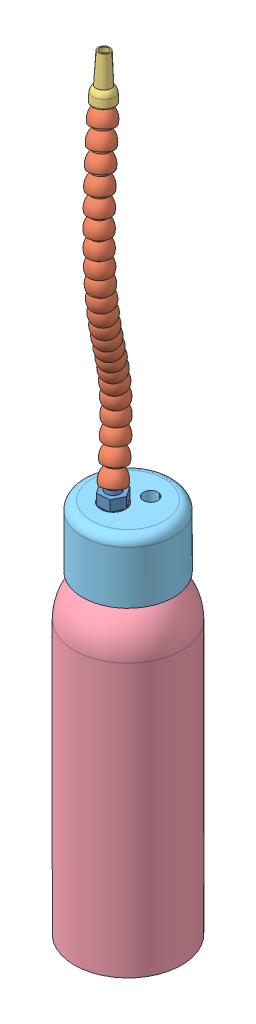
SolidWorks assembly _Robocup_Assembly_Thermos_Static_Wide_Straw_, configuration Default. Lengths in mm.
Overall size (75.21 554.8 95.58).
27 component instances, 5 part files, 7 mates.
Components (placement in the parent):
- Coolant Pipe.stp-1: Coolant Pipe.stp [Default] at (-3.81 14.5 6.5991) x (0.568385 0 0.822762) z (-0.822762 0 0.568385) size (74.23 300.91 26.18)
  - Coolant Bolt.stp-1: Coolant Bolt.stp [Default] x (-1 0 0) z (0 0 1) size (17.61 27.5 15.25)
  - Connectors.stp-1: Connectors.stp [Default] at (-2.2835 3.6671 -0.0362) x (-0.321951 -0.100327 -0.941426) z (0.285439 -0.958386 0.00452) size (18.3 18.3 20)
  - Connectors.stp-2: Connectors.stp [Default] at (-0.9485 62.1668 -0.2193) x (0.834188 -0.338799 0.435138) z (-0.378337 -0.925657 0.00458) size (18.3 18.3 20)
  - Connectors.stp-3: Connectors.stp [Default] at (-7.0218 39.1054 -0.1142) x (0.974617 -0.052931 0.217534) z (-0.054998 -0.99848 0.003454) size (18.3 18.3 20)
  - Connectors.stp-4: Connectors.stp [Default] at (-7.018 27.1423 -0.0887) x (-0.288884 -0.031731 -0.956838) z (0.11095 -0.993826 -0.00054) size (18.3 18.3 20)
  - Connectors.stp-5: Connectors.stp [Default] at (10.0914 83.4503 -0.3173) x (0.525964 -0.304704 -0.794051) z (-0.497138 -0.867664 0.003658) size (18.3 18.3 20)
  - Connectors.stp-6: Connectors.stp [Default] at (4.2645 72.9625 -0.2712) x (0.886562 -0.462353 0.015441) z (-0.462461 -0.88663 0.004202) size (18.3 18.3 20)
  - Connectors.stp-7: Connectors.stp [Default] at (-4.9174 50.8742 -0.1644) x (0.803108 -0.192004 0.56405) z (-0.235547 -0.971852 0.004557) size (18.3 18.3 20)
  - Connectors.stp-8: Connectors.stp [Default] at (16.0513 93.8656 -0.3564) x (0.86534 -0.495122 -0.077724) z (-0.496415 -0.86808 0.003062) size (18.3 18.3 20)
  - Connectors.stp-9: Connectors.stp [Default] at (35.5838 137.5772 -0.4345) x (0.770438 -0.236558 0.592002) z (-0.293738 -0.955886 0.000312) size (18.3 18.3 20)
  - Connectors.stp-10: Connectors.stp [Default] at (38.4122 149.228 -0.4322) x (0.672162 -0.141658 -0.726727) z (-0.20668 -0.978409 -0.000445) size (18.3 18.3 20)
  - Connectors.stp-11: Connectors.stp [Default] at (31.7619 126.2108 -0.4277) x (0.912958 -0.361121 0.189996) z (-0.368012 -0.929821 0.001063) size (18.3 18.3 20)
  - Connectors.stp-12: Connectors.stp [Default] at (21.8052 104.3949 -0.3882) x (-0.461711 0.244191 -0.852756) z (-0.471034 -0.882112 0.002437) size (18.3 18.3 20)
  - Connectors.stp-13: Connectors.stp [Default] at (-5.2287 15.2947 -0.0801) x (0.757626 0.173214 -0.629285) z (0.225426 -0.974255 0.003232) size (18.3 18.3 20)
  - Connectors.stp-14: Connectors.stp [Default] at (27.1083 115.1559 -0.4121) x (0.901968 -0.4265 -0.067469) z (-0.427365 -0.904078 0.001774) size (18.3 18.3 20)
  - Coolant Pipe Nozzle.stp-1: Coolant Pipe Nozzle.stp [Default] at (27.898 246.6708 -0.2231) x (-0.153795 -0.02183 0.987862) z (0.098368 -0.995128 -0.006677) size (15 15 30)
  - Connectors.stp-15: Connectors.stp [Default] at (40.4307 185.0487 -0.3789) x (0.938856 0.053217 -0.340172) z (0.055817 -0.998439 -0.002147) size (18.3 18.3 20)
  - Connectors.stp-16: Connectors.stp [Default] at (39.2092 196.9799 -0.3507) x (0.937442 0.118696 -0.327281) z (0.124773 -0.992182 -0.002445) size (18.3 18.3 20)
  - Connectors.stp-17: Connectors.stp [Default] at (40.784 173.0623 -0.4029) x (0.972219 -0.02226 -0.233011) z (-0.023301 -0.999727 -0.001718) size (18.3 18.3 20)
  - Connectors.stp-18: Connectors.stp [Default] at (40.1447 161.0902 -0.4212) x (0.882181 -0.100002 -0.460169) z (-0.113225 -0.993569 -0.001143) size (18.3 18.3 20)
  - Connectors.stp-19: Connectors.stp [Default] at (31.9646 232.2183 -0.2574) x (0.793284 0.199128 0.575369) z (0.245233 -0.969461 -0.002594) size (18.3 18.3 20)
  - Connectors.stp-20: Connectors.stp [Default] at (37.2637 208.8167 -0.3201) x (0.26581 0.051415 -0.962653) z (0.180811 -0.983514 -0.002604) size (18.3 18.3 20)
  - Connectors.stp-21: Connectors.stp [Default] at (28.861 243.8093 -0.2266) x (0.725081 0.197806 0.659645) z (0.26534 -0.964151 -0.002545) size (18.3 18.3 20)
  - Connectors.stp-22: Connectors.stp [Default] at (34.7978 220.5587 -0.2886) x (0.975424 0.217793 -0.033387) z (0.217828 -0.975984 -0.002632) size (18.3 18.3 20)
- Thermos-1: Thermos [Default] at (0 -262.89 0) size (74.93 250.19 74.93)
- Robocup_Lid_Thermos_Static_Wide_Straw-1: Robocup_Lid_Thermos_Static_Wide_Straw [Default] at (0 -44.45 0) size (63.5 43.72 63.5)
Mates (geometry in assembly coordinates):
- Coincident1: coincident aligned: plane of Thermos-1 through (0 -262.89 0) normal (0 0 1)
- Coincident2: coincident aligned: plane of Thermos-1 through (0 -262.89 0) normal (1 0 0)
- Coincident4: coincident aligned: plane of Static lid thermos-1 through (0 0 0) normal (0 1 0)
- Concentric2: concentric anti-aligned: cylinder of Thermos-1 through (0 -262.89 0) axis (0 -1 0) radius 24.384; cylinder of Robocup_Lid_Thermos_Static-1 through (0 -43.18 0) axis (0 1 0) radius 31.75
- Coincident5: coincident anti-aligned: plane of Thermos-1 through (24.384 -12.7 0) normal (0 1 0); plane of Static lid thermos-1 through (0 -12.7 0) normal (0 -1 0)
- Coincident6: coincident: plane of Coolant Pipe.stp-1/Coolant Bolt.stp-1 through (-11.2551 0 41.4649) normal (0 -1 0); plane of Static lid thermos-1 through (0 0 0) normal (0 1 0)
- Concentric3: concentric aligned: cylinder of Coolant Pipe.stp-1/Coolant Bolt.stp-1 through (-3.81 9 6.5991) axis (0 1 0) radius 5; circle of Robocup_Lid_Thermos_Static_Wide_Straw-1
